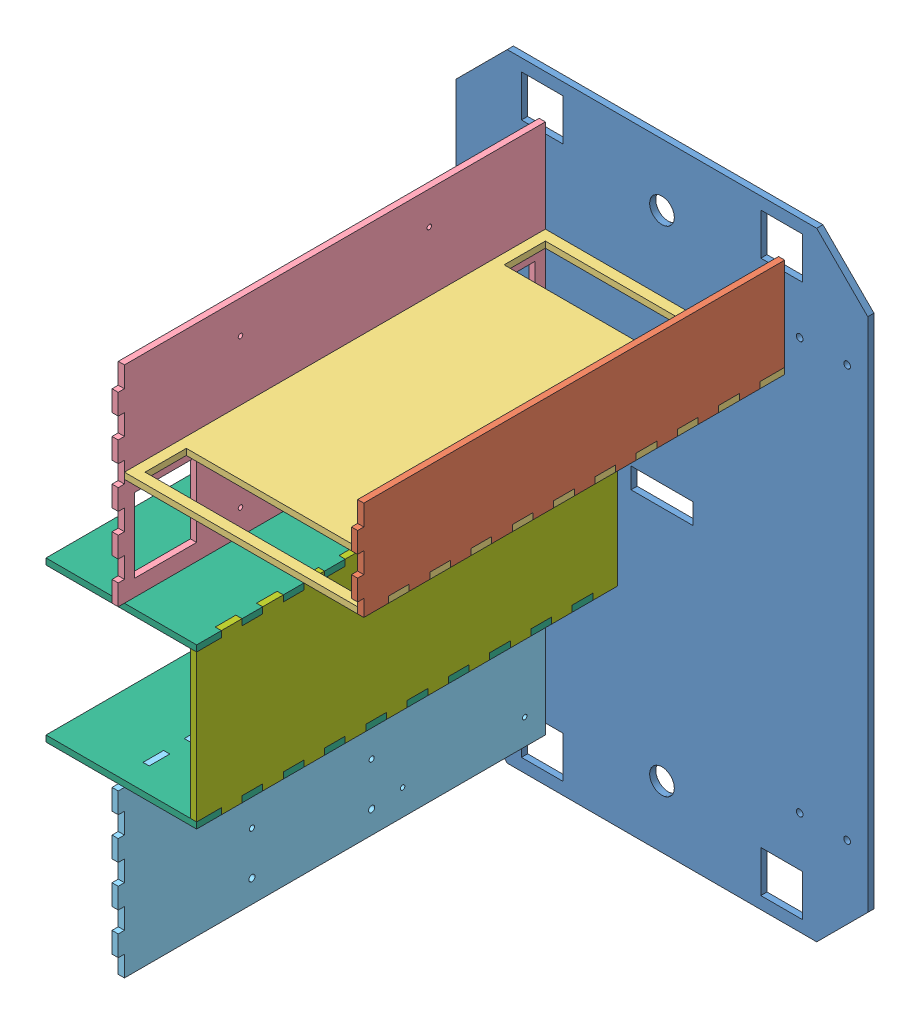
SolidWorks assembly Assemblage premier etage Robot 2, configuration Défaut. Lengths in mm.
Overall size (199.5 299.5 210).
8 component instances, 7 part files, 29 mates.
Components (placement in the parent):
- Plaque robot premier étage V.1-1: Plaque robot premier étage V.1 [Défaut] at (-174.7487 149.7487 -3) x (-1 0 0) z (0 0 1) size (199.5 299.5 3)
- Plaque côté batterie-1: Plaque côté batterie [Default] at (-43.25 128.6487 204) x (0 -1 0) z (0 0 1) size (48 3 210)
- Plaque arrière batterie-2: Plaque arrière batterie [Default] at (-43.25 80.6487 0) x (-1 0 0) z (0 0 -1) size (119 3 204)
- Plaque support carte alim-1: Plaque support carte alim [Default] at (-159.25 128.6487 204) x (0 -1 0) z (0 0 1) size (103 3 210)
- Plaque support droite-1: Plaque support droite [Default] at (-156.25 -48.6513 0) x (0 -1 0) z (0 0 -1) size (83 3 210)
- Cagette vis côté-1: Cagette vis côté [Default] at (-194.25 28.6487 0) x (1 0 0) z (0 0 -1) size (73 3 204)
- Cagette vis côté-2: Cagette vis côté [Default] at (-194.25 -45.6513 0) x (1 0 0) z (0 0 -1) size (73 3 204)
- Cagette vis arrière-1: Cagette vis arrière [Default] at (-124.25 -10.0013 0) x (0 1 0) z (0 0 -1) size (77.3 3 204)
Mates (geometry in assembly coordinates):
- Coïncidente95: coincident anti-aligned: plane of SG90 Servo-1 through (82.2791 -10.8598 645.789) normal (-0.161572 0.718869 0.676108); plane of Bras sortie de billes-1 through (48.9167 -7.7483 634.5079) normal (0.161572 -0.718869 -0.676108)
- Coaxiale41: concentric anti-aligned: circle of SG90 Servo-1; cylinder of Bras sortie de billes-1 through (81.4713 -7.2655 649.1695) axis (0.161572 -0.718869 -0.676108) radius 3.125
- Parallèle11: parallel anti-aligned: plane of plaque_cartes_éléctroniques_2-1 through (-85.6262 126.0582 579.7101) normal (-1 0 0); plane of CIRCUIT BOARD,TEENSY 4.10-1 through (-95.6262 -84.4126 471.1676) normal (1 0 0)
- Distance11: distance = 10 mm anti-aligned: plane of CIRCUIT BOARD,TEENSY 4.10-1 through (-95.6262 -84.4126 471.1676) normal (1 0 0); plane of plaque_cartes_éléctroniques_2-1 through (-85.6262 126.0582 579.7101) normal (-1 0 0)
- Parallèle12: parallel aligned: plane of plaque_cartes_éléctroniques_2-1 through (-82.6262 126.0582 399.7101) normal (0 0 -1); plane of CIRCUIT BOARD,TEENSY 4.10-1 through (-97.2242 -100.9226 411.4776) normal (0 0 -1)
- Parallèle13: parallel anti-aligned: plane of plaque_cartes_éléctroniques_2-1 through (-85.6262 126.0582 579.7101) normal (-1 0 0); plane of Raspberry Pi 4 Model B-1 through (-90.6262 -76.0331 525.4361) normal (1 0 0)
- Parallèle14: parallel aligned: plane of plaque_cartes_éléctroniques_2-1 through (-82.6262 126.0582 399.7101) normal (0 0 -1); plane of Raspberry Pi 4 Model B-1 through (-92.2262 -48.0331 482.9361) normal (0 0 -1)
- Distance12: distance = 5 mm anti-aligned: plane of Raspberry Pi 4 Model B-1 through (-90.6262 -76.0331 525.4361) normal (1 0 0); plane of plaque_cartes_éléctroniques_2-1 through (-85.6262 126.0582 579.7101) normal (-1 0 0)
- Coincident7: coincident anti-aligned: line of Plaque robot premier étage V.1-1 through (-44.2409 53.8313 301.529) axis (0 1 0); line of Plaque côté batterie-1 through (-44.2409 63.8313 301.529) axis (0 -1 0)
- Coincident8: coincident: point of Plaque robot premier étage V.1-1; moEndPointRef_w of Plaque côté batterie-1
- Coincident12: coincident anti-aligned: line of Plaque côté batterie-1 through (-44.2409 28.8313 316.529) axis (0 0 -1); line of Plaque arrière batterie-2 through (-44.2409 28.8313 304.529) axis (0 0 1)
- Coincident13: coincident aligned: line of Plaque côté batterie-1 through (-44.2409 28.8313 304.529) axis (-1 0 0); line of Plaque arrière batterie-2 through (-44.2409 28.8313 304.529) axis (-1 0 0)
- Coincident14: coincident anti-aligned: line of Plaque robot premier étage V.1-1 through (-163.2409 63.8313 301.529) axis (0 -1 0); line of Plaque support carte alim-1 through (-163.2409 53.8313 301.529) axis (0 1 0)
- Distance18: distance = 0 mm: line of Plaque arrière batterie-2 through (-159.25 83.6487 7) axis (0 0 1); line of Plaque support carte alim-1 through (-159.25 83.6487 7) axis (0 0 1)
- Coincident21: coincident anti-aligned: line of Plaque robot premier étage V.1-1 through (-163.2409 -163.4687 301.529) axis (0 -1 0); line of Plaque support droite-1 through (-163.2409 -173.4687 301.529) axis (0 1 0)
- Coincident22: coincident anti-aligned: line of Plaque robot premier étage V.1-1 through (-163.2409 -173.4687 301.529) axis (1 0 0); line of Plaque support droite-1 through (-160.2409 -173.4687 301.529) axis (-1 0 0)
- Parallel5: parallel anti-aligned: line of Cagette vis côté-1 through (-128.2409 -26.1687 304.529) axis (0 0 1); line of Cagette vis arrière-1 through (-125.2409 -26.1687 316.529) axis (0 0 -1)
- Parallel6: parallel anti-aligned: plane of Cagette vis côté-1 through (-198.2409 -29.1687 304.529) normal (0 -1 0); plane of Cagette vis arrière-1 through (-128.2409 -26.1687 304.529) normal (0 1 0)
- Coïncidente161: coincident aligned: plane of Cagette vis côté-1 through (-125.2409 -26.1687 304.529) normal (1 0 0); plane of Cagette vis arrière-1 through (-125.2409 -64.8187 304.529) normal (1 0 0)
- Coïncidente162: coincident aligned: plane of Cagette vis côté-1 through (-198.2409 -29.1687 508.529) normal (0 0 1); plane of Cagette vis arrière-1 through (-125.2409 -64.8187 508.529) normal (0 0 1)
- Coïncidente163: coincident aligned: plane of Cagette vis côté-1 through (-198.2409 -26.1687 304.529) normal (0 1 0); plane of Cagette vis arrière-1 through (-128.2409 -26.1687 304.529) normal (0 1 0)
- Coïncidente166: coincident aligned: plane of Plaque support carte alim-1 through (-163.2409 -29.1687 508.529) normal (0 -1 0); plane of Cagette vis côté-1 through (-198.2409 -29.1687 304.529) normal (0 -1 0)
- Coïncidente168: coincident anti-aligned: plane of Plaque robot premier étage V.1-1 through (-178.7396 94.9313 304.529) normal (0 0 1); plane of Cagette vis côté-1 through (-198.2409 -29.1687 304.529) normal (0 0 -1)
- Coïncidente169: coincident anti-aligned: plane of Cagette vis côté-2 through (-198.2409 -100.4687 304.529) normal (0 1 0); plane of Cagette vis arrière-1 through (-125.2409 -100.4687 304.529) normal (0 -1 0)
- Coïncidente171: coincident aligned: plane of Cagette vis côté-2 through (-125.2409 -100.4687 304.529) normal (1 0 0); plane of Cagette vis arrière-1 through (-125.2409 -64.8187 304.529) normal (1 0 0)
- Coïncidente172: coincident anti-aligned: plane of Cagette vis côté-2 through (-125.2409 -103.4687 486.529) normal (0 0 1); plane of Cagette vis arrière-1 through (-128.2409 -103.4687 486.529) normal (0 0 -1)
- Coïncidente173: coincident aligned: plane of Plaque arrière batterie-2 through (-163.2409 25.8313 444.529) normal (-1 0 0); plane of Plaque support carte alim-1 through (-163.2409 73.8313 508.529) normal (-1 0 0)
- Coïncidente174: coincident anti-aligned: plane of Plaque support carte alim-1 through (-160.2409 73.8313 508.529) normal (1 0 0); plane of Cagette vis côté-1 through (-160.2409 -26.1687 456.529) normal (-1 0 0)
- Coïncidente248: coincident: unknown of Plaque robot premier étage V.1-1
